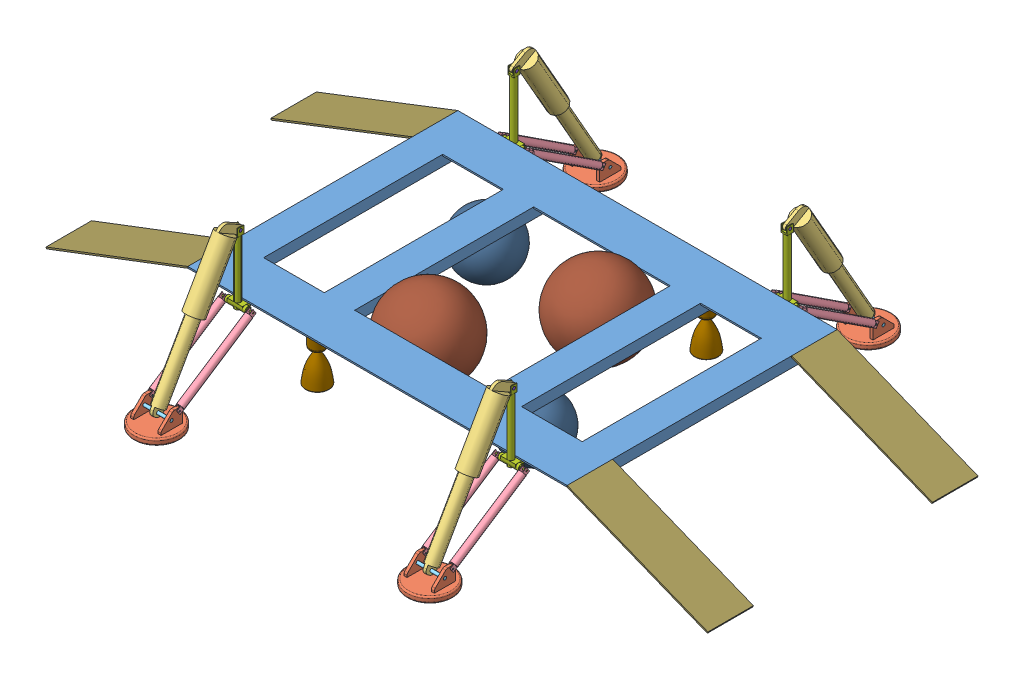
SolidWorks assembly lander_base_assem, configuration Default. Lengths in mm.
Overall size (4362.63 1074.03 3190.9).
51 component instances, 12 part files, 37 mates.
Components (placement in the parent):
- Lander base-1: Lander base [Default] at (714.6592 -461.0878 -63.8597) size (2500 70 1780)
- leg_aluminum_rev-1: leg_aluminum_rev [Default] at (365.8635 -910.6524 482.3383) x (0 0.000985 1) z (-1 0 0) size (725.04 964.3 300)
  - base_leg-1: base_leg [Default] at (9.2435 -7.9699 0.537) size (300 140 300)
  - Main_leg-1: Main_leg [Default] at (-240.1972 521.872 0.537) x (0 0 -1) z (0.869495 0.493942 0) size (120 996.55 163.86)
  - Support_leg-1: Support_leg [Default] at (-74.206 133.9648 -89.463) x (0 0 -1) z (0.548366 0.836238 0) size (45 600 45)
  - leg_pin-1: leg_pin [Default] at (9.2435 82.777 -99.463) x (0 0 1) z (-0.667547 0.744568 0) size (200 20 20)
  - Support_leg-2: Support_leg [Default] at (-74.206 133.9648 90.537) x (0 0 -1) z (0.548366 0.836238 0) size (45 600 45)
  - leg_support_pin-1: leg_support_pin [Default] at (-40.7565 112.0301 -76.463) x (0 0 -1) z (1 0 0) size (26 10 10)
  - leg_support_pin-2: leg_support_pin [Default] at (-40.7565 112.0301 103.537) x (0 0 -1) z (1 0 0) size (26 10 10)
  - leg_joiner-1: leg_joiner [Default] at (-525.7944 410.0826 0.537) x (1 -0.000985 0) z (0 0 1) size (60 470.09 206)
  - leg_joiner_pin-1: leg_joiner_pin [Default] at (-525.3511 860.1724 -19.463) size (20 20 40)
- leg_aluminum_rev-2: leg_aluminum_rev [Default] at (364.7896 -910.6524 -2390.0576) x (0 0.000985 -1) z (1 0 0) size (725.04 964.3 300)
  - base_leg-1: base_leg [Default] at (9.2435 -7.9699 0.537) size (300 140 300)
  - Main_leg-1: Main_leg [Default] at (-240.1972 521.872 0.537) x (0 0 -1) z (0.869495 0.493942 0) size (120 996.55 163.86)
  - Support_leg-1: Support_leg [Default] at (-74.206 133.9648 -89.463) x (0 0 -1) z (0.548366 0.836238 0) size (45 600 45)
  - leg_pin-1: leg_pin [Default] at (9.2435 82.777 -99.463) x (0 0 1) z (-0.667547 0.744568 0) size (200 20 20)
  - Support_leg-2: Support_leg [Default] at (-74.206 133.9648 90.537) x (0 0 -1) z (0.548366 0.836238 0) size (45 600 45)
  - leg_support_pin-1: leg_support_pin [Default] at (-40.7565 112.0301 -76.463) x (0 0 -1) z (1 0 0) size (26 10 10)
  - leg_support_pin-2: leg_support_pin [Default] at (-40.7565 112.0301 103.537) x (0 0 -1) z (1 0 0) size (26 10 10)
  - leg_joiner-1: leg_joiner [Default] at (-525.7944 410.0826 0.537) x (1 -0.000985 0) z (0 0 1) size (60 470.09 206)
  - leg_joiner_pin-1: leg_joiner_pin [Default] at (-525.3511 860.1724 -19.463) size (20 20 40)
- leg_aluminum_rev-3: leg_aluminum_rev [Default] at (-1436.5452 -910.6524 -2390.0576) x (0 0.000985 -1) z (1 0 0) size (725.04 964.3 300)
  - base_leg-1: base_leg [Default] at (9.2435 -7.9699 0.537) size (300 140 300)
  - Main_leg-1: Main_leg [Default] at (-240.1972 521.872 0.537) x (0 0 -1) z (0.869495 0.493942 0) size (120 996.55 163.86)
  - Support_leg-1: Support_leg [Default] at (-74.206 133.9648 -89.463) x (0 0 -1) z (0.548366 0.836238 0) size (45 600 45)
  - leg_pin-1: leg_pin [Default] at (9.2435 82.777 -99.463) x (0 0 1) z (-0.667547 0.744568 0) size (200 20 20)
  - Support_leg-2: Support_leg [Default] at (-74.206 133.9648 90.537) x (0 0 -1) z (0.548366 0.836238 0) size (45 600 45)
  - leg_support_pin-1: leg_support_pin [Default] at (-40.7565 112.0301 -76.463) x (0 0 -1) z (1 0 0) size (26 10 10)
  - leg_support_pin-2: leg_support_pin [Default] at (-40.7565 112.0301 103.537) x (0 0 -1) z (1 0 0) size (26 10 10)
  - leg_joiner-1: leg_joiner [Default] at (-525.7944 410.0826 0.537) x (1 -0.000985 0) z (0 0 1) size (60 470.09 206)
  - leg_joiner_pin-1: leg_joiner_pin [Default] at (-525.3511 860.1724 -19.463) size (20 20 40)
- leg_aluminum_rev-4: leg_aluminum_rev [Default] at (-1435.4713 -910.6524 482.3383) x (0 0.000985 1) z (-1 0 0) size (725.04 964.3 300)
  - base_leg-1: base_leg [Default] at (9.2435 -7.9699 0.537) size (300 140 300)
  - Main_leg-1: Main_leg [Default] at (-240.1972 521.872 0.537) x (0 0 -1) z (0.869495 0.493942 0) size (120 996.55 163.86)
  - Support_leg-1: Support_leg [Default] at (-74.206 133.9648 -89.463) x (0 0 -1) z (0.548366 0.836238 0) size (45 600 45)
  - leg_pin-1: leg_pin [Default] at (9.2435 82.777 -99.463) x (0 0 1) z (-0.667547 0.744568 0) size (200 20 20)
  - Support_leg-2: Support_leg [Default] at (-74.206 133.9648 90.537) x (0 0 -1) z (0.548366 0.836238 0) size (45 600 45)
  - leg_support_pin-1: leg_support_pin [Default] at (-40.7565 112.0301 -76.463) x (0 0 -1) z (1 0 0) size (26 10 10)
  - leg_support_pin-2: leg_support_pin [Default] at (-40.7565 112.0301 103.537) x (0 0 -1) z (1 0 0) size (26 10 10)
  - leg_joiner-1: leg_joiner [Default] at (-525.7944 410.0826 0.537) x (1 -0.000985 0) z (0 0 1) size (60 470.09 206)
  - leg_joiner_pin-1: leg_joiner_pin [Default] at (-525.3511 860.1724 -19.463) size (20 20 40)
- MR_80b-1: MR_80b [Default] at (-1081.6322 -841.0878 -214.0715) size (153.97 380 153.97)
- MR_80b-2: MR_80b [Default] at (16.7233 -838.4394 -1679.7382) x (0.999992 0 0.004071) z (-0.004071 0 0.999992) size (153.97 380 153.97)
- Helium_tank-1: Helium_tank [Default] at (203.1711 -638.5192 -541.9795) x (0.94256 0.329358 0.055716) z (0.325345 -0.942975 0.070353) size (400 400 400)
- Helium_tank-2: Helium_tank [Default] at (-953.3371 -635.4687 -1361.8199) x (0.977489 0.124684 0.170201) z (-0.107578 -0.399417 0.910436) size (400 400 400)
- Hydrazine_tank-1: Hydrazine_tank [Default] at (-643.5463 -334.2768 -539.5578) x (0.363071 0.900077 0.240916) z (0.071543 0.230867 -0.970352) size (550 550 550)
- Hydrazine_tank-2: Hydrazine_tank [Default] at (-75.2899 -529.4709 -1409.1331) x (0.901296 0.217178 -0.374832) z (0.418463 -0.660267 0.623647) size (550 550 550)
- ramp-1: ramp [Default] at (-1781.7357 -460.4154 -1543.8597) x (0.932756 0.360509 0) z (0 0 1) size (1000 10 300)
- ramp-2: ramp [Default] at (-1781.7786 -460.4318 -63.8597) x (0.934403 0.356219 0) z (0 0 1) size (1000 10 300)
- ramp-3: ramp [Default] at (1639.1629 -832.3921 -1543.8597) x (0.928224 -0.372022 0) z (0 0 1) size (1000 10 300)
- ramp-4: ramp [Default] at (1639.0067 -832.7706 -63.8597) x (0.928071 -0.372402 0) z (0 0 1) size (1000 10 300)
Mates (geometry in assembly coordinates):
- Coincident2: coincident anti-aligned: plane of Lander base-1 through (714.6592 -461.0878 -63.8597) normal (0 -1 0); plane of leg_aluminum_rev-1/leg_joiner-1 through (315.3266 -461.0878 -23.8597) normal (0 1 0)
- Coincident5: coincident anti-aligned: plane of Lander base-1 through (714.6592 -461.0878 -63.8597) normal (0 -1 0); plane of leg_aluminum_rev-4/leg_joiner-1 through (-1486.0082 -461.0878 -23.8597) normal (0 1 0)
- Coincident7: coincident anti-aligned: plane of Lander base-1 through (714.6592 -461.0878 -1843.8597) normal (0 -1 0); plane of leg_aluminum_rev-2/leg_joiner-1 through (415.3266 -461.0878 -1883.8597) normal (0 1 0)
- Perpendicular2: perpendicular: line of Lander base-1; line of leg_aluminum_rev-2/leg_joiner-1
- Tangent2: tangent: line of Lander base-1; cylinder of leg_aluminum_rev-2/leg_joiner-1
- Perpendicular3: perpendicular: line of Lander base-1; line of leg_aluminum_rev-4/leg_joiner-1
- Tangent3: tangent: line of Lander base-1; cylinder of leg_aluminum_rev-4/leg_joiner-1
- Perpendicular4: perpendicular: line of Lander base-1; line of leg_aluminum_rev-1/leg_joiner-1
- Tangent4: tangent: line of Lander base-1; cylinder of leg_aluminum_rev-1/leg_joiner-1
- Coincident16: coincident anti-aligned: plane of Lander base-1 through (714.6592 -461.0878 -1843.8597) normal (0 -1 0); plane of leg_aluminum_rev-3/leg_joiner-1 through (-1386.0082 -461.0878 -1883.8597) normal (0 1 0)
- Perpendicular5: perpendicular: line of Lander base-1; line of leg_aluminum_rev-3/leg_joiner-1
- Tangent6: tangent: line of Lander base-1; cylinder of leg_aluminum_rev-3/leg_joiner-1
- Distance1: distance = 300 mm: line of Lander base-1; line of leg_aluminum_rev-1/leg_joiner-1
- Distance2: distance = 300 mm: line of Lander base-1; line of leg_aluminum_rev-2/leg_joiner-1
- Distance3: distance = 300 mm: line of Lander base-1; line of leg_aluminum_rev-4/leg_joiner-1
- Distance4: distance = 300 mm: line of Lander base-1; line of leg_aluminum_rev-3/leg_joiner-1
- Coincident17: coincident anti-aligned: plane of Lander base-1 through (714.6592 -461.0878 -63.8597) normal (0 -1 0); plane of MR_80b-1 through (-1081.6322 -461.0878 -214.0715) normal (0 1 0)
- Tangent14: tangent: line of Lander base-1; sphere of Helium_tank-2
- Tangent15: tangent: line of Lander base-1; sphere of Helium_tank-2
- Tangent19: tangent: line of Lander base-1; sphere of Helium_tank-1
- Tangent22: tangent: line of Lander base-1; sphere of Helium_tank-1
- Tangent24: tangent: line of Lander base-1; sphere of Hydrazine_tank-1
- Tangent25: tangent: line of Lander base-1; sphere of Hydrazine_tank-1
- Tangent26: tangent: line of Lander base-1; sphere of Hydrazine_tank-2
- Tangent27: tangent: line of Lander base-1; sphere of Hydrazine_tank-2
- Coincident20: coincident anti-aligned: line of Lander base-1; line of ramp-1
- Coincident21: coincident: point of Lander base-1; point of ramp-1
- Coincident23: coincident anti-aligned: line of Lander base-1; line of ramp-2
- Coincident24: coincident: point of Lander base-1; point of ramp-2
- Coincident25: coincident anti-aligned: line of Lander base-1; line of ramp-3
- Coincident26: coincident: point of Lander base-1; point of ramp-3
- Coincident27: coincident anti-aligned: line of Lander base-1; line of ramp-4
- Coincident28: coincident: point of Lander base-1; point of ramp-4
- Angle1: planar angle = 1.919862 rad aligned: plane of Lander base-1 through (714.6592 -451.0878 -63.8597) normal (0 1 0); plane of ramp-1 through (-1785.3408 -451.0878 -1543.8597) normal (0.939693 0.34202 0)
- Angle2: planar angle = 1.919862 rad aligned: plane of Lander base-1 through (714.6592 -451.0878 -63.8597) normal (0 1 0); plane of ramp-2 through (-1785.3408 -451.0878 -63.8597) normal (0.939693 0.34202 0)
- Angle3: planar angle = 1.919862 rad aligned: plane of Lander base-1 through (714.6592 -451.0878 -63.8597) normal (0 1 0); plane of ramp-3 through (1056.6793 488.6048 -1543.8597) normal (-0.939693 0.34202 0)
- Angle4: planar angle = 1.919862 rad aligned: plane of Lander base-1 through (714.6592 -451.0878 -63.8597) normal (0 1 0); plane of ramp-4 through (1056.6793 488.6048 -63.8597) normal (-0.939693 0.34202 0)
